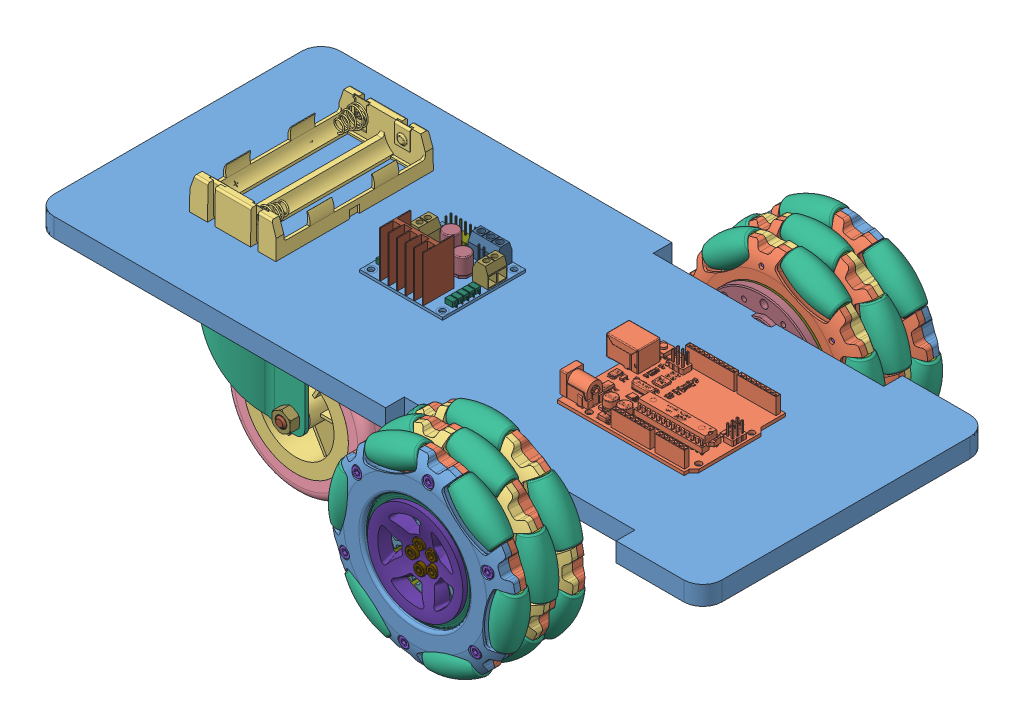
SolidWorks assembly Assem1, configuration Default. Lengths in mm.
Overall size (350 189.45 233.78).
324 component instances, 39 part files, 13 mates.
Components (placement in the parent):
- Base-1: Base [Default] at (-9.4539 132.6385 147.3537) size (350 10 150)
- Arduino Uno-1: Arduino Uno [Default] at (217.3211 144.2885 250.2775) x (0.005201 0 0.999986) z (-0.999986 0 0.005201) size (53.34 15.25 74.93)
- Assem2-1: Assem2 [Default] at (66.4468 55.8385 236.4759) x (1 0 0) z (0 1 0) size (101.4 70 114.3)
  - wheel-1: wheel [Default] at origin size (55 26.04 55)
  - tire-3: tire [Default] at (0 13 0) size (75 26 75)
  - Washer-4: Washer [Default] at (-0.0006 25.9444 0) x (0.999924 0.012354 0) z (0 0 1) size (15 1 15)
  - Washer-5: Washer [Default] at (-0.0006 0.0556 0) x (0.999924 -0.012354 0) z (0 0 -1) size (15 1 15)
  - wheel carrier-1: wheel carrier [Default] at (-28.9 13 57.6974) x (1 0 0) z (0 -1 0) size (61.1 84 49)
  - bearing -1: bearing  [Default] at (-28.9 13 57.6544) x (0 1 0) z (1 0 0) size (20 28 20)
  - Support plate -2: Support plate  [Default] at (-28.9 13 74.8) x (1 0 0) z (0 -1 0) size (70 28 70)
  - Ring-2: Ring [Default] at (-28.9 13.5 75.1) x (1 0 0) z (0 -1 0) size (12.09 1 12.84)
  - pipe-1: pipe [Default] at (0.3799 30.8549 0) x (0.999924 -0.012354 0) z (0 0 1) size (9 26 9)
  - screw M6-1: screw M6 [Default] at (0.2 -9 0.0106) size (9.53 41 11)
  - screw nut m6-1: screw nut m6 [Default] at (0.2 -8 0) size (9.53 5.33 11)
- Driect Drive Omni Wheel-1: Driect Drive Omni Wheel [Default] at (229.9584 120.1385 292.0369) x (0 0 1) z (-0.934942 -0.3548 0) size (54.71 135.89 136)
  - Direct Drive Motor-2: Direct Drive Motor [Default] at origin size (53.66 65 65)
    - DDM Bace-1: DDM Bace [Default] at origin size (45.5 65 65)
    - DDm Stator laminet-1: DDm Stator laminet [Default] at (32.5 0 0) x (0 1 0) z (0 0 1) size (53.5 22 53.5)
    - W 61809-2RS1-1: W 61809-2RS1 [Default] at (36 0 0) size (7 58 58)
    - DDM Rotor-1: DDM Rotor [Default] at (21.75 0 0) x (0 0 -1) z (0 1 0) size (65 42.5 65)
    - W 61809-2RS1-2: W 61809-2RS1 [Default] at origin size (7 58 58)
    - DDM Cap-1: DDM Cap [Default] at (30 0 0) size (16.16 50 50)
    - DDM M3-15mmscrew-1: DDM M3-15mmscrew [Valor predeterminado] at (39.1 -4.8541 3.5267) x (0 -1 0) z (0 0 1) size (5.5 13.1 5.5)
    - DDM M3-15mmscrew-2: DDM M3-15mmscrew [Valor predeterminado] at (39.1 1.8541 5.7063) x (0 -0.309017 0.951057) z (0 0.951057 0.309017) size (5.5 13.1 5.5)
    - DDM M3-15mmscrew-3: DDM M3-15mmscrew [Valor predeterminado] at (39.1 6 0) x (0 0.809017 0.587785) z (0 0.587785 -0.809017) size (5.5 13.1 5.5)
    - DDM M3-15mmscrew-4: DDM M3-15mmscrew [Valor predeterminado] at (39.1 1.8541 -5.7063) x (0 0.809017 -0.587785) z (0 -0.587785 -0.809017) size (5.5 13.1 5.5)
    - DDM M3-15mmscrew-5: DDM M3-15mmscrew [Valor predeterminado] at (39.1 -4.8541 -3.5267) x (0 -0.309017 -0.951057) z (0 -0.951057 0.309017) size (5.5 13.1 5.5)
  - DDOW Part 2-1: DDOW Part 2 [Default] at (38 0 0) x (0 0 1) z (0 1 0) size (97 9.21 95.55)
  - DDOW Part 5-1: DDOW Part 5 [Default] at (38 0 0) x (0 0 -1) z (0 1 0) size (97 9.21 95.55)
  - DDOW Part 3-1: DDOW Part 3 [Default] at (23 0 0) x (0 -0.37175 0.928333) z (0 0.928333 0.37175) size (97 9.21 95.55)
  - DDOW Part 5-2: DDOW Part 5 [Default] at (23 0 0) x (0 0.37175 -0.928333) z (0 0.928333 0.37175) size (97 9.21 95.55)
  - DDOW Part 3-2: DDOW Part 3 [Default] at (8 0 0) x (0 -0.666839 0.745202) z (0 0.745202 0.666839) size (97 9.21 95.55)
  - DDOW Part 5-3: DDOW Part 5 [Default] at (8 0 0) x (0 -0.311944 -0.9501) z (0 0.9501 -0.311944) size (97 9.21 95.55)
  - DDOW Roller Shaft-1: DDOW Roller Shaft [Default] at (38 -42.5 18) x (1 0 0) z (0 1 0) size (3 36 3)
  - DDOW Roller Shaft-2: DDOW Roller Shaft [Default] at (23 -46.1456 0.9106) x (1 0 0) z (0 0.928333 0.37175) size (3 36 3)
  - DDOW Roller Shaft-3: DDOW Roller Shaft [Default] at (8 -43.6742 -14.927) x (1 0 0) z (0 0.745202 0.666839) size (3 36 3)
  - DDOW Roller Shaft-4: DDOW Roller Shaft [Default] at (38 -5.6615 45.8061) x (1 0 0) z (0 0.5 -0.866025) size (3 36 3)
  - DDOW Roller Shaft-5: DDOW Roller Shaft [Default] at (38 36.8385 27.8061) x (1 0 0) z (0 -0.5 -0.866025) size (3 36 3)
  - DDOW Roller Shaft-6: DDOW Roller Shaft [Default] at (38 42.5 -18) x (1 0 0) z (0 -1 0) size (3 36 3)
  - DDOW Roller Shaft-7: DDOW Roller Shaft [Default] at (38 5.6615 -45.8061) x (1 0 0) z (0 -0.5 0.866025) size (3 36 3)
  - DDOW Roller Shaft-8: DDOW Roller Shaft [Default] at (38 -36.8385 -27.8061) x (1 0 0) z (0 0.5 0.866025) size (3 36 3)
  - DDOW Roller Shaft-9: DDOW Roller Shaft [Default] at (23 -22.2842 40.4186) x (1 0 0) z (0 0.786111 -0.618085) size (3 36 3)
  - DDOW Roller Shaft-10: DDOW Roller Shaft [Default] at (23 23.8614 39.508) x (1 0 0) z (0 -0.142222 -0.989835) size (3 36 3)
  - DDOW Roller Shaft-11: DDOW Roller Shaft [Default] at (23 46.1456 -0.9106) x (1 0 0) z (0 -0.928333 -0.37175) size (3 36 3)
  - DDOW Roller Shaft-12: DDOW Roller Shaft [Default] at (23 22.2842 -40.4186) x (1 0 0) z (0 -0.786111 0.618085) size (3 36 3)
  - DDOW Roller Shaft-13: DDOW Roller Shaft [Default] at (23 -23.8614 -39.508) x (1 0 0) z (0 0.142222 0.989835) size (3 36 3)
  - DDOW Roller Shaft-14: DDOW Roller Shaft [Default] at (8 -34.7643 30.3594) x (1 0 0) z (0 0.9501 -0.311944) size (3 36 3)
  - DDOW Roller Shaft-15: DDOW Roller Shaft [Default] at (8 8.9099 45.2865) x (1 0 0) z (0 0.204899 -0.978783) size (3 36 3)
  - DDOW Roller Shaft-16: DDOW Roller Shaft [Default] at (8 43.6742 14.927) x (1 0 0) z (0 -0.745202 -0.666839) size (3 36 3)
  - DDOW Roller Shaft-17: DDOW Roller Shaft [Default] at (8 34.7643 -30.3594) x (1 0 0) z (0 -0.9501 0.311944) size (3 36 3)
  - DDOW Roller Shaft-18: DDOW Roller Shaft [Default] at (8 -8.9099 -45.2865) x (1 0 0) z (0 -0.204899 0.978783) size (3 36 3)
  - DDOW Suport Shaft-1: DDOW Suport Shaft [Default] at (38 -42.5 0) x (0 0 -1) z (1 0 0) size (27.4 9 9)
  - DDOW Roller-1: DDOW Roller [Default] at (38 -42.5 0) x (0 0 -1) z (1 0 0) size (29 15 15)
  - DDOW Suport Shaft-2: DDOW Suport Shaft [Default] at (23 -39.4542 -15.7994) x (0 0.37175 -0.928333) z (1 0 0) size (27.4 9 9)
  - DDOW Suport Shaft-3: DDOW Suport Shaft [Default] at (8 -31.6711 -28.3407) x (0 0.666839 -0.745202) z (1 0 0) size (27.4 9 9)
  - DDOW Roller-2: DDOW Roller [Default] at (23 -39.4542 -15.7994) x (0 0.37175 -0.928333) z (0.999544 0.028039 0.011228) size (29 15 15)
  - DDOW Roller-3: DDOW Roller [Default] at (8 -31.6711 -28.3407) x (0 -0.666839 0.745202) z (0.923728 0.285449 0.255432) size (29 15 15)
  - W 638_3 R-2RS1-1: W 638_3 R-2RS1 [Default] at (8 -22.0019 -39.1461) x (0 -0.666839 0.745202) z (-1 0 0) size (3 8.1 8.1)
  - W 638_3 R-2RS1-2: W 638_3 R-2RS1 [Default] at (8 -41.3402 -17.5352) x (0 0.666839 -0.745202) z (-0.937928 -0.258458 -0.23128) size (3 8.1 8.1)
  - W 638_3 R-2RS1-3: W 638_3 R-2RS1 [Default] at (23 -34.0638 -29.2602) x (0 -0.37175 0.928333) z (-1 0 0) size (3 8.1 8.1)
  - W 638_3 R-2RS1-4: W 638_3 R-2RS1 [Default] at (23 -44.8445 -2.3385) x (0 0.37175 -0.928333) z (-0.923728 -0.355597 -0.142398) size (3 8.1 8.1)
  - W 638_3 R-2RS1-5: W 638_3 R-2RS1 [Default] at (38 -42.5 14.5) x (0 0 -1) z (-0.923728 -0.383049 0) size (3 8.1 8.1)
  - W 638_3 R-2RS1-6: W 638_3 R-2RS1 [Default] at (38 -42.5 -14.5) x (0 0 1) z (-1 0 0) size (3 8.1 8.1)
  - W 638_3 R-2RS1-7: W 638_3 R-2RS1 [Default] at (38 -33.8074 29.5561) x (0 0.866025 0.5) z (-1 0 0) size (3 8.1 8.1)
  - W 638_3 R-2RS1-8: W 638_3 R-2RS1 [Default] at (38 8.6926 44.0561) x (0 0.866025 -0.5) z (-1 0 0) size (3 8.1 8.1)
  - W 638_3 R-2RS1-9: W 638_3 R-2RS1 [Default] at (38 42.5 14.5) x (0 0 -1) z (-1 0 0) size (3 8.1 8.1)
  - W 638_3 R-2RS1-10: W 638_3 R-2RS1 [Default] at (38 33.8074 -29.5561) x (0 -0.866025 -0.5) z (-1 0 0) size (3 8.1 8.1)
  - W 638_3 R-2RS1-11: W 638_3 R-2RS1 [Default] at (38 -8.6926 -44.0561) x (0 -0.866025 0.5) z (-1 0 0) size (3 8.1 8.1)
  - W 638_3 R-2RS1-12: W 638_3 R-2RS1 [Default] at (38 -8.6926 44.0561) x (0 -0.866025 -0.5) z (-0.923728 -0.191525 0.33173) size (3 8.1 8.1)
  - W 638_3 R-2RS1-13: W 638_3 R-2RS1 [Default] at (38 33.8074 29.5561) x (0 -0.866025 0.5) z (-0.923728 0.191525 0.33173) size (3 8.1 8.1)
  - W 638_3 R-2RS1-14: W 638_3 R-2RS1 [Default] at (38 42.5 -14.5) x (0 0 1) z (-0.923728 0.383049 0) size (3 8.1 8.1)
  - W 638_3 R-2RS1-15: W 638_3 R-2RS1 [Default] at (38 8.6926 -44.0561) x (0 0.866025 0.5) z (-0.923728 0.191525 -0.33173) size (3 8.1 8.1)
  - W 638_3 R-2RS1-16: W 638_3 R-2RS1 [Default] at (38 -33.8074 -29.5561) x (0 0.866025 -0.5) z (-0.923728 -0.191525 -0.33173) size (3 8.1 8.1)
  - W 638_3 R-2RS1-17: W 638_3 R-2RS1 [Default] at (23 -24.4475 37.6672) x (0 -0.618085 -0.786111) z (-0.923728 -0.301119 0.236757) size (3 8.1 8.1)
  - W 638_3 R-2RS1-18: W 638_3 R-2RS1 [Default] at (23 20.397 40.0058) x (0 -0.989835 0.142222) z (-0.923728 0.054478 0.379155) size (3 8.1 8.1)
  - W 638_3 R-2RS1-19: W 638_3 R-2RS1 [Default] at (23 44.8445 2.3385) x (0 -0.37175 0.928333) z (-0.923728 0.355597 0.142398) size (3 8.1 8.1)
  - W 638_3 R-2RS1-20: W 638_3 R-2RS1 [Default] at (23 24.4475 -37.6672) x (0 0.618085 0.786111) z (-0.923728 0.301119 -0.236757) size (3 8.1 8.1)
  - W 638_3 R-2RS1-21: W 638_3 R-2RS1 [Default] at (23 -20.397 -40.0058) x (0 0.989835 -0.142222) z (-0.923728 -0.054478 -0.379155) size (3 8.1 8.1)
  - W 638_3 R-2RS1-22: W 638_3 R-2RS1 [Default] at (23 -42.372 14.87) x (0 0.618085 0.786111) z (-1 0 0) size (3 8.1 8.1)
  - W 638_3 R-2RS1-23: W 638_3 R-2RS1 [Default] at (23 -8.3082 44.1302) x (0 0.989835 -0.142222) z (-1 0 0) size (3 8.1 8.1)
  - W 638_3 R-2RS1-24: W 638_3 R-2RS1 [Default] at (23 34.0638 29.2602) x (0 0.37175 -0.928333) z (-1 0 0) size (3 8.1 8.1)
  - W 638_3 R-2RS1-25: W 638_3 R-2RS1 [Default] at (23 42.372 -14.87) x (0 -0.618085 -0.786111) z (-1 0 0) size (3 8.1 8.1)
  - W 638_3 R-2RS1-26: W 638_3 R-2RS1 [Default] at (23 8.3082 -44.1302) x (0 -0.989835 0.142222) z (-1 0 0) size (3 8.1 8.1)
  - W 638_3 R-2RS1-27: W 638_3 R-2RS1 [Default] at (8 -35.8561 27.0341) x (0 -0.311944 -0.9501) z (-0.937928 -0.329523 0.108192) size (3 8.1 8.1)
  - W 638_3 R-2RS1-28: W 638_3 R-2RS1 [Default] at (8 5.4842 44.5693) x (0 -0.978783 -0.204899) z (-0.937928 -0.071065 0.339471) size (3 8.1 8.1)
  - W 638_3 R-2RS1-29: W 638_3 R-2RS1 [Default] at (8 41.3402 17.5352) x (0 -0.666839 0.745202) z (-0.937928 0.258458 0.23128) size (3 8.1 8.1)
  - W 638_3 R-2RS1-30: W 638_3 R-2RS1 [Default] at (8 35.8561 -27.0341) x (0 0.311944 0.9501) z (-0.937928 0.329523 -0.108192) size (3 8.1 8.1)
  - W 638_3 R-2RS1-31: W 638_3 R-2RS1 [Default] at (8 -5.4842 -44.5693) x (0 0.978783 0.204899) z (-0.937928 0.071065 -0.339471) size (3 8.1 8.1)
  - W 638_3 R-2RS1-32: W 638_3 R-2RS1 [Default] at (8 -44.9025 -0.5188) x (0 0.311944 0.9501) z (-1 0 0) size (3 8.1 8.1)
  - W 638_3 R-2RS1-33: W 638_3 R-2RS1 [Default] at (8 -22.9006 38.6273) x (0 0.978783 0.204899) z (-1 0 0) size (3 8.1 8.1)
  - W 638_3 R-2RS1-34: W 638_3 R-2RS1 [Default] at (8 22.0019 39.1461) x (0 0.666839 -0.745202) z (-1 0 0) size (3 8.1 8.1)
  - W 638_3 R-2RS1-35: W 638_3 R-2RS1 [Default] at (8 44.9025 0.5188) x (0 -0.311944 -0.9501) z (-1 0 0) size (3 8.1 8.1)
  - W 638_3 R-2RS1-36: W 638_3 R-2RS1 [Default] at (8 22.9006 -38.6273) x (0 -0.978783 -0.204899) z (-1 0 0) size (3 8.1 8.1)
  - DDOW Roller-4: DDOW Roller [Default] at (8 -40.3793 13.2576) x (0 0.311944 0.9501) z (0.923728 0.363935 -0.11949) size (29 15 15)
  - DDOW Roller-5: DDOW Roller [Default] at (8 -8.7082 41.5983) x (0 0.978783 0.204899) z (0.923728 0.078486 -0.374922) size (29 15 15)
  - DDOW Roller-6: DDOW Roller [Default] at (8 31.6711 28.3407) x (0 0.666839 -0.745202) z (0.923728 -0.285449 -0.255432) size (29 15 15)
  - DDOW Roller-7: DDOW Roller [Default] at (8 40.3793 -13.2576) x (0 -0.311944 -0.9501) z (0.923728 -0.363935 0.11949) size (29 15 15)
  - DDOW Roller-8: DDOW Roller [Default] at (8 8.7082 -41.5983) x (0 -0.978783 -0.204899) z (0.923728 -0.078486 0.374922) size (29 15 15)
  - DDOW Roller-9: DDOW Roller [Default] at (23 -33.4097 26.2686) x (0 -0.618085 -0.786111) z (0.999544 0.023743 -0.018668) size (29 15 15)
  - DDOW Roller-10: DDOW Roller [Default] at (23 6.0444 42.068) x (0 -0.989835 0.142222) z (0.999544 -0.004296 -0.029896) size (29 15 15)
  - DDOW Roller-11: DDOW Roller [Default] at (23 39.4542 15.7994) x (0 -0.37175 0.928333) z (0.999544 -0.028039 -0.011228) size (29 15 15)
  - DDOW Roller-12: DDOW Roller [Default] at (23 33.4097 -26.2686) x (0 0.618085 0.786111) z (0.999544 -0.023743 0.018668) size (29 15 15)
  - DDOW Roller-13: DDOW Roller [Default] at (23 -6.0444 -42.068) x (0 0.989835 -0.142222) z (0.999544 0.004296 0.029896) size (29 15 15)
  - DDOW Suport Shaft-4: DDOW Suport Shaft [Default] at (8 -40.3793 13.2576) x (0 -0.311944 -0.9501) z (1 0 0) size (27.4 9 9)
  - DDOW Suport Shaft-5: DDOW Suport Shaft [Default] at (8 -8.7082 41.5983) x (0 -0.978783 -0.204899) z (1 0 0) size (27.4 9 9)
  - DDOW Suport Shaft-6: DDOW Suport Shaft [Default] at (8 31.6711 28.3407) x (0 -0.666839 0.745202) z (1 0 0) size (27.4 9 9)
  - DDOW Suport Shaft-7: DDOW Suport Shaft [Default] at (8 40.3793 -13.2576) x (0 0.311944 0.9501) z (1 0 0) size (27.4 9 9)
  - DDOW Suport Shaft-8: DDOW Suport Shaft [Default] at (8 8.7082 -41.5983) x (0 0.978783 0.204899) z (1 0 0) size (27.4 9 9)
  - DDOW Suport Shaft-9: DDOW Suport Shaft [Default] at (23 -33.4097 26.2686) x (0 -0.618085 -0.786111) z (1 0 0) size (27.4 9 9)
  - DDOW Suport Shaft-10: DDOW Suport Shaft [Default] at (23 6.0444 42.068) x (0 -0.989835 0.142222) z (1 0 0) size (27.4 9 9)
  - DDOW Suport Shaft-11: DDOW Suport Shaft [Default] at (23 39.4542 15.7994) x (0 -0.37175 0.928333) z (1 0 0) size (27.4 9 9)
  - DDOW Suport Shaft-12: DDOW Suport Shaft [Default] at (23 33.4097 -26.2686) x (0 0.618085 0.786111) z (1 0 0) size (27.4 9 9)
  - DDOW Suport Shaft-13: DDOW Suport Shaft [Default] at (23 -6.0444 -42.068) x (0 0.989835 -0.142222) z (1 0 0) size (27.4 9 9)
  - DDOW Roller-14: DDOW Roller [Default] at (38 -21.25 36.8061) x (0 -0.866025 -0.5) z (1 0 0) size (29 15 15)
  - DDOW Roller-15: DDOW Roller [Default] at (38 21.25 36.8061) x (0 -0.866025 0.5) z (1 0 0) size (29 15 15)
  - DDOW Roller-16: DDOW Roller [Default] at (38 42.5 0) x (0 0 1) z (1 0 0) size (29 15 15)
  - DDOW Roller-17: DDOW Roller [Default] at (38 21.25 -36.8061) x (0 0.866025 0.5) z (1 0 0) size (29 15 15)
  - DDOW Roller-18: DDOW Roller [Default] at (38 -21.25 -36.8061) x (0 0.866025 -0.5) z (1 0 0) size (29 15 15)
  - DDOW Suport Shaft-14: DDOW Suport Shaft [Default] at (38 -21.25 36.8061) x (0 -0.866025 -0.5) z (1 0 0) size (27.4 9 9)
  - DDOW Suport Shaft-15: DDOW Suport Shaft [Default] at (38 21.25 36.8061) x (0 -0.866025 0.5) z (1 0 0) size (27.4 9 9)
  - DDOW Suport Shaft-16: DDOW Suport Shaft [Default] at (38 42.5 0) x (0 0 1) z (1 0 0) size (27.4 9 9)
  - DDOW Suport Shaft-17: DDOW Suport Shaft [Default] at (38 21.25 -36.8061) x (0 0.866025 0.5) z (1 0 0) size (27.4 9 9)
  - DDOW Suport Shaft-18: DDOW Suport Shaft [Default] at (38 -21.25 -36.8061) x (0 0.866025 -0.5) z (1 0 0) size (27.4 9 9)
  - DDOW Roller Shaft-19: DDOW Roller Shaft [Default] at (8 -34.7643 30.3594) x (1 0 0) z (0 0.9501 -0.311944) size (3 36 3)
  - DDOW Roller Shaft-20: DDOW Roller Shaft [Default] at (8 8.9099 45.2865) x (1 0 0) z (0 0.204899 -0.978783) size (3 36 3)
  - DDOW Roller Shaft-21: DDOW Roller Shaft [Default] at (8 43.6742 14.927) x (1 0 0) z (0 -0.745202 -0.666839) size (3 36 3)
  - DDOW Roller Shaft-22: DDOW Roller Shaft [Default] at (8 34.7643 -30.3594) x (1 0 0) z (0 -0.9501 0.311944) size (3 36 3)
  - DDOW Roller Shaft-23: DDOW Roller Shaft [Default] at (8 -8.9099 -45.2865) x (1 0 0) z (0 -0.204899 0.978783) size (3 36 3)
  - DDOW Roller Shaft-24: DDOW Roller Shaft [Default] at (23 -22.2842 40.4186) x (1 0 0) z (0 0.786111 -0.618085) size (3 36 3)
  - DDOW Roller Shaft-25: DDOW Roller Shaft [Default] at (23 23.8614 39.508) x (1 0 0) z (0 -0.142222 -0.989835) size (3 36 3)
  - DDOW Roller Shaft-26: DDOW Roller Shaft [Default] at (23 46.1456 -0.9106) x (1 0 0) z (0 -0.928333 -0.37175) size (3 36 3)
  - DDOW Roller Shaft-27: DDOW Roller Shaft [Default] at (23 22.2842 -40.4186) x (1 0 0) z (0 -0.786111 0.618085) size (3 36 3)
  - DDOW Roller Shaft-28: DDOW Roller Shaft [Default] at (23 -23.8614 -39.508) x (1 0 0) z (0 0.142222 0.989835) size (3 36 3)
  - DDOW Roller Shaft-29: DDOW Roller Shaft [Default] at (38 -5.6615 45.8061) x (1 0 0) z (0 0.5 -0.866025) size (3 36 3)
  - DDOW Roller Shaft-30: DDOW Roller Shaft [Default] at (38 36.8385 27.8061) x (1 0 0) z (0 -0.5 -0.866025) size (3 36 3)
  - DDOW Roller Shaft-31: DDOW Roller Shaft [Default] at (38 42.5 -18) x (1 0 0) z (0 -1 0) size (3 36 3)
  - DDOW Roller Shaft-32: DDOW Roller Shaft [Default] at (38 5.6615 -45.8061) x (1 0 0) z (0 -0.5 0.866025) size (3 36 3)
  - DDOW Roller Shaft-33: DDOW Roller Shaft [Default] at (38 -36.8385 -27.8061) x (1 0 0) z (0 0.5 0.866025) size (3 36 3)
  - DDOW M3-15mmscrew-1: DDOW M3-15mmscrew [Valor predeterminado] at (42 -34.641 20) x (0 -1 0) z (0 0 1) size (5.5 13.1 5.5)
  - DDOW M3-15mmscrew-2: DDOW M3-15mmscrew [Valor predeterminado] at (27 -14.87 37.1333) x (0 -1 0) z (0 0 1) size (5.5 13.1 5.5)
  - DDOW M3-15mmscrew-3: DDOW M3-15mmscrew [Valor predeterminado] at (12 12.4778 38.004) x (0 -1 0) z (0 0 1) size (5.5 13.1 5.5)
  - DDOW M3-15mmscrew-5: DDOW M3-15mmscrew [Valor predeterminado] at (12 39.1513 8.196) x (0 -0.5 0.866025) z (0 0.866025 0.5) size (5.5 13.1 5.5)
  - DDOW M3-15mmscrew-6: DDOW M3-15mmscrew [Valor predeterminado] at (12 26.6736 -29.8081) x (0 0.5 0.866025) z (0 0.866025 -0.5) size (5.5 13.1 5.5)
  - DDOW M3-15mmscrew-7: DDOW M3-15mmscrew [Valor predeterminado] at (12 -12.4778 -38.004) x (0 1 0) z (0 0 -1) size (5.5 13.1 5.5)
  - DDOW M3-15mmscrew-8: DDOW M3-15mmscrew [Valor predeterminado] at (12 -39.1513 -8.196) x (0 0.5 -0.866025) z (0 -0.866025 -0.5) size (5.5 13.1 5.5)
  - DDOW M3-15mmscrew-9: DDOW M3-15mmscrew [Valor predeterminado] at (12 -26.6736 29.8081) x (0 -0.5 -0.866025) z (0 -0.866025 0.5) size (5.5 13.1 5.5)
  - DDOW M3-15mmscrew-10: DDOW M3-15mmscrew [Valor predeterminado] at (27 24.7234 31.4445) x (0 -0.5 0.866025) z (0 0.866025 0.5) size (5.5 13.1 5.5)
  - DDOW M3-15mmscrew-11: DDOW M3-15mmscrew [Valor predeterminado] at (27 39.5934 -5.6889) x (0 0.5 0.866025) z (0 0.866025 -0.5) size (5.5 13.1 5.5)
  - DDOW M3-15mmscrew-12: DDOW M3-15mmscrew [Valor predeterminado] at (27 14.87 -37.1333) x (0 1 0) z (0 0 -1) size (5.5 13.1 5.5)
  - DDOW M3-15mmscrew-13: DDOW M3-15mmscrew [Valor predeterminado] at (27 -24.7234 -31.4445) x (0 0.5 -0.866025) z (0 -0.866025 -0.5) size (5.5 13.1 5.5)
  - DDOW M3-15mmscrew-14: DDOW M3-15mmscrew [Valor predeterminado] at (27 -39.5934 5.6889) x (0 -0.5 -0.866025) z (0 -0.866025 0.5) size (5.5 13.1 5.5)
  - DDOW M3-15mmscrew-15: DDOW M3-15mmscrew [Valor predeterminado] at (42 0 40) x (0 -0.5 0.866025) z (0 0.866025 0.5) size (5.5 13.1 5.5)
  - DDOW M3-15mmscrew-16: DDOW M3-15mmscrew [Valor predeterminado] at (42 34.641 20) x (0 0.5 0.866025) z (0 0.866025 -0.5) size (5.5 13.1 5.5)
  - DDOW M3-15mmscrew-17: DDOW M3-15mmscrew [Valor predeterminado] at (42 34.641 -20) x (0 1 0) z (0 0 -1) size (5.5 13.1 5.5)
  - DDOW M3-15mmscrew-18: DDOW M3-15mmscrew [Valor predeterminado] at (42 0 -40) x (0 0.5 -0.866025) z (0 -0.866025 -0.5) size (5.5 13.1 5.5)
  - DDOW M3-15mmscrew-19: DDOW M3-15mmscrew [Valor predeterminado] at (42 -34.641 -20) x (0 -0.5 -0.866025) z (0 -0.866025 0.5) size (5.5 13.1 5.5)
- Pololu-25D-12V-21kgcm-DCmotor-2: Pololu-25D-12V-21kgcm-DCmotor [Varsayılan] at (229.9584 120.1385 242.6369) x (-0.746606 -0.665266 0) z (0 0 1) size (26 29.5 78.1)
- Driect Drive Omni Wheel-2: Driect Drive Omni Wheel [Default] at (230.5822 120.1385 152.6705) x (0 0 -1) z (0.946615 0.322367 0) size (54.71 135.89 136)
  - Direct Drive Motor-2: Direct Drive Motor [Default] at origin size (53.66 65 65)
    - DDM Bace-1: DDM Bace [Default] at origin size (45.5 65 65)
    - DDm Stator laminet-1: DDm Stator laminet [Default] at (32.5 0 0) x (0 1 0) z (0 0 1) size (53.5 22 53.5)
    - W 61809-2RS1-1: W 61809-2RS1 [Default] at (36 0 0) size (7 58 58)
    - DDM Rotor-1: DDM Rotor [Default] at (21.75 0 0) x (0 0 -1) z (0 1 0) size (65 42.5 65)
    - W 61809-2RS1-2: W 61809-2RS1 [Default] at origin size (7 58 58)
    - DDM Cap-1: DDM Cap [Default] at (30 0 0) size (16.16 50 50)
    - DDM M3-15mmscrew-1: DDM M3-15mmscrew [Valor predeterminado] at (39.1 -4.8541 3.5267) x (0 -1 0) z (0 0 1) size (5.5 13.1 5.5)
    - DDM M3-15mmscrew-2: DDM M3-15mmscrew [Valor predeterminado] at (39.1 1.8541 5.7063) x (0 -0.309017 0.951057) z (0 0.951057 0.309017) size (5.5 13.1 5.5)
    - DDM M3-15mmscrew-3: DDM M3-15mmscrew [Valor predeterminado] at (39.1 6 0) x (0 0.809017 0.587785) z (0 0.587785 -0.809017) size (5.5 13.1 5.5)
    - DDM M3-15mmscrew-4: DDM M3-15mmscrew [Valor predeterminado] at (39.1 1.8541 -5.7063) x (0 0.809017 -0.587785) z (0 -0.587785 -0.809017) size (5.5 13.1 5.5)
    - DDM M3-15mmscrew-5: DDM M3-15mmscrew [Valor predeterminado] at (39.1 -4.8541 -3.5267) x (0 -0.309017 -0.951057) z (0 -0.951057 0.309017) size (5.5 13.1 5.5)
  - DDOW Part 2-1: DDOW Part 2 [Default] at (38 0 0) x (0 0 1) z (0 1 0) size (97 9.21 95.55)
  - DDOW Part 5-1: DDOW Part 5 [Default] at (38 0 0) x (0 0 -1) z (0 1 0) size (97 9.21 95.55)
  - DDOW Part 3-1: DDOW Part 3 [Default] at (23 0 0) x (0 -0.37175 0.928333) z (0 0.928333 0.37175) size (97 9.21 95.55)
  - DDOW Part 5-2: DDOW Part 5 [Default] at (23 0 0) x (0 0.37175 -0.928333) z (0 0.928333 0.37175) size (97 9.21 95.55)
  - DDOW Part 3-2: DDOW Part 3 [Default] at (8 0 0) x (0 -0.666839 0.745202) z (0 0.745202 0.666839) size (97 9.21 95.55)
  - DDOW Part 5-3: DDOW Part 5 [Default] at (8 0 0) x (0 -0.311944 -0.9501) z (0 0.9501 -0.311944) size (97 9.21 95.55)
  - DDOW Roller Shaft-1: DDOW Roller Shaft [Default] at (38 -42.5 18) x (1 0 0) z (0 1 0) size (3 36 3)
  - DDOW Roller Shaft-2: DDOW Roller Shaft [Default] at (23 -46.1456 0.9106) x (1 0 0) z (0 0.928333 0.37175) size (3 36 3)
  - DDOW Roller Shaft-3: DDOW Roller Shaft [Default] at (8 -43.6742 -14.927) x (1 0 0) z (0 0.745202 0.666839) size (3 36 3)
  - DDOW Roller Shaft-4: DDOW Roller Shaft [Default] at (38 -5.6615 45.8061) x (1 0 0) z (0 0.5 -0.866025) size (3 36 3)
  - DDOW Roller Shaft-5: DDOW Roller Shaft [Default] at (38 36.8385 27.8061) x (1 0 0) z (0 -0.5 -0.866025) size (3 36 3)
  - DDOW Roller Shaft-6: DDOW Roller Shaft [Default] at (38 42.5 -18) x (1 0 0) z (0 -1 0) size (3 36 3)
  - DDOW Roller Shaft-7: DDOW Roller Shaft [Default] at (38 5.6615 -45.8061) x (1 0 0) z (0 -0.5 0.866025) size (3 36 3)
  - DDOW Roller Shaft-8: DDOW Roller Shaft [Default] at (38 -36.8385 -27.8061) x (1 0 0) z (0 0.5 0.866025) size (3 36 3)
  - DDOW Roller Shaft-9: DDOW Roller Shaft [Default] at (23 -22.2842 40.4186) x (1 0 0) z (0 0.786111 -0.618085) size (3 36 3)
  - DDOW Roller Shaft-10: DDOW Roller Shaft [Default] at (23 23.8614 39.508) x (1 0 0) z (0 -0.142222 -0.989835) size (3 36 3)
  - DDOW Roller Shaft-11: DDOW Roller Shaft [Default] at (23 46.1456 -0.9106) x (1 0 0) z (0 -0.928333 -0.37175) size (3 36 3)
  - DDOW Roller Shaft-12: DDOW Roller Shaft [Default] at (23 22.2842 -40.4186) x (1 0 0) z (0 -0.786111 0.618085) size (3 36 3)
  - DDOW Roller Shaft-13: DDOW Roller Shaft [Default] at (23 -23.8614 -39.508) x (1 0 0) z (0 0.142222 0.989835) size (3 36 3)
  - DDOW Roller Shaft-14: DDOW Roller Shaft [Default] at (8 -34.7643 30.3594) x (1 0 0) z (0 0.9501 -0.311944) size (3 36 3)
  - DDOW Roller Shaft-15: DDOW Roller Shaft [Default] at (8 8.9099 45.2865) x (1 0 0) z (0 0.204899 -0.978783) size (3 36 3)
  - DDOW Roller Shaft-16: DDOW Roller Shaft [Default] at (8 43.6742 14.927) x (1 0 0) z (0 -0.745202 -0.666839) size (3 36 3)
  - DDOW Roller Shaft-17: DDOW Roller Shaft [Default] at (8 34.7643 -30.3594) x (1 0 0) z (0 -0.9501 0.311944) size (3 36 3)
  - DDOW Roller Shaft-18: DDOW Roller Shaft [Default] at (8 -8.9099 -45.2865) x (1 0 0) z (0 -0.204899 0.978783) size (3 36 3)
  - DDOW Suport Shaft-1: DDOW Suport Shaft [Default] at (38 -42.5 0) x (0 0 -1) z (1 0 0) size (27.4 9 9)
  - DDOW Roller-1: DDOW Roller [Default] at (38 -42.5 0) x (0 0 -1) z (1 0 0) size (29 15 15)
  - DDOW Suport Shaft-2: DDOW Suport Shaft [Default] at (23 -39.4542 -15.7994) x (0 0.37175 -0.928333) z (1 0 0) size (27.4 9 9)
  - DDOW Suport Shaft-3: DDOW Suport Shaft [Default] at (8 -31.6711 -28.3407) x (0 0.666839 -0.745202) z (1 0 0) size (27.4 9 9)
  - DDOW Roller-2: DDOW Roller [Default] at (23 -39.4542 -15.7994) x (0 0.37175 -0.928333) z (0.999544 0.028039 0.011228) size (29 15 15)
  - DDOW Roller-3: DDOW Roller [Default] at (8 -31.6711 -28.3407) x (0 -0.666839 0.745202) z (0.923728 0.285449 0.255432) size (29 15 15)
  - W 638_3 R-2RS1-1: W 638_3 R-2RS1 [Default] at (8 -22.0019 -39.1461) x (0 -0.666839 0.745202) z (-1 0 0) size (3 8.1 8.1)
  - W 638_3 R-2RS1-2: W 638_3 R-2RS1 [Default] at (8 -41.3402 -17.5352) x (0 0.666839 -0.745202) z (-0.937928 -0.258458 -0.23128) size (3 8.1 8.1)
  - W 638_3 R-2RS1-3: W 638_3 R-2RS1 [Default] at (23 -34.0638 -29.2602) x (0 -0.37175 0.928333) z (-1 0 0) size (3 8.1 8.1)
  - W 638_3 R-2RS1-4: W 638_3 R-2RS1 [Default] at (23 -44.8445 -2.3385) x (0 0.37175 -0.928333) z (-0.923728 -0.355597 -0.142398) size (3 8.1 8.1)
  - W 638_3 R-2RS1-5: W 638_3 R-2RS1 [Default] at (38 -42.5 14.5) x (0 0 -1) z (-0.923728 -0.383049 0) size (3 8.1 8.1)
  - W 638_3 R-2RS1-6: W 638_3 R-2RS1 [Default] at (38 -42.5 -14.5) x (0 0 1) z (-1 0 0) size (3 8.1 8.1)
  - W 638_3 R-2RS1-7: W 638_3 R-2RS1 [Default] at (38 -33.8074 29.5561) x (0 0.866025 0.5) z (-1 0 0) size (3 8.1 8.1)
  - W 638_3 R-2RS1-8: W 638_3 R-2RS1 [Default] at (38 8.6926 44.0561) x (0 0.866025 -0.5) z (-1 0 0) size (3 8.1 8.1)
  - W 638_3 R-2RS1-9: W 638_3 R-2RS1 [Default] at (38 42.5 14.5) x (0 0 -1) z (-1 0 0) size (3 8.1 8.1)
  - W 638_3 R-2RS1-10: W 638_3 R-2RS1 [Default] at (38 33.8074 -29.5561) x (0 -0.866025 -0.5) z (-1 0 0) size (3 8.1 8.1)
  - W 638_3 R-2RS1-11: W 638_3 R-2RS1 [Default] at (38 -8.6926 -44.0561) x (0 -0.866025 0.5) z (-1 0 0) size (3 8.1 8.1)
  - W 638_3 R-2RS1-12: W 638_3 R-2RS1 [Default] at (38 -8.6926 44.0561) x (0 -0.866025 -0.5) z (-0.923728 -0.191525 0.33173) size (3 8.1 8.1)
  - W 638_3 R-2RS1-13: W 638_3 R-2RS1 [Default] at (38 33.8074 29.5561) x (0 -0.866025 0.5) z (-0.923728 0.191525 0.33173) size (3 8.1 8.1)
  - W 638_3 R-2RS1-14: W 638_3 R-2RS1 [Default] at (38 42.5 -14.5) x (0 0 1) z (-0.923728 0.383049 0) size (3 8.1 8.1)
  - W 638_3 R-2RS1-15: W 638_3 R-2RS1 [Default] at (38 8.6926 -44.0561) x (0 0.866025 0.5) z (-0.923728 0.191525 -0.33173) size (3 8.1 8.1)
  - W 638_3 R-2RS1-16: W 638_3 R-2RS1 [Default] at (38 -33.8074 -29.5561) x (0 0.866025 -0.5) z (-0.923728 -0.191525 -0.33173) size (3 8.1 8.1)
  - W 638_3 R-2RS1-17: W 638_3 R-2RS1 [Default] at (23 -24.4475 37.6672) x (0 -0.618085 -0.786111) z (-0.923728 -0.301119 0.236757) size (3 8.1 8.1)
  - W 638_3 R-2RS1-18: W 638_3 R-2RS1 [Default] at (23 20.397 40.0058) x (0 -0.989835 0.142222) z (-0.923728 0.054478 0.379155) size (3 8.1 8.1)
  - W 638_3 R-2RS1-19: W 638_3 R-2RS1 [Default] at (23 44.8445 2.3385) x (0 -0.37175 0.928333) z (-0.923728 0.355597 0.142398) size (3 8.1 8.1)
  - W 638_3 R-2RS1-20: W 638_3 R-2RS1 [Default] at (23 24.4475 -37.6672) x (0 0.618085 0.786111) z (-0.923728 0.301119 -0.236757) size (3 8.1 8.1)
  - W 638_3 R-2RS1-21: W 638_3 R-2RS1 [Default] at (23 -20.397 -40.0058) x (0 0.989835 -0.142222) z (-0.923728 -0.054478 -0.379155) size (3 8.1 8.1)
  - W 638_3 R-2RS1-22: W 638_3 R-2RS1 [Default] at (23 -42.372 14.87) x (0 0.618085 0.786111) z (-1 0 0) size (3 8.1 8.1)
  - W 638_3 R-2RS1-23: W 638_3 R-2RS1 [Default] at (23 -8.3082 44.1302) x (0 0.989835 -0.142222) z (-1 0 0) size (3 8.1 8.1)
  - W 638_3 R-2RS1-24: W 638_3 R-2RS1 [Default] at (23 34.0638 29.2602) x (0 0.37175 -0.928333) z (-1 0 0) size (3 8.1 8.1)
  - W 638_3 R-2RS1-25: W 638_3 R-2RS1 [Default] at (23 42.372 -14.87) x (0 -0.618085 -0.786111) z (-1 0 0) size (3 8.1 8.1)
  - W 638_3 R-2RS1-26: W 638_3 R-2RS1 [Default] at (23 8.3082 -44.1302) x (0 -0.989835 0.142222) z (-1 0 0) size (3 8.1 8.1)
  - W 638_3 R-2RS1-27: W 638_3 R-2RS1 [Default] at (8 -35.8561 27.0341) x (0 -0.311944 -0.9501) z (-0.937928 -0.329523 0.108192) size (3 8.1 8.1)
  - W 638_3 R-2RS1-28: W 638_3 R-2RS1 [Default] at (8 5.4842 44.5693) x (0 -0.978783 -0.204899) z (-0.937928 -0.071065 0.339471) size (3 8.1 8.1)
  - W 638_3 R-2RS1-29: W 638_3 R-2RS1 [Default] at (8 41.3402 17.5352) x (0 -0.666839 0.745202) z (-0.937928 0.258458 0.23128) size (3 8.1 8.1)
  - W 638_3 R-2RS1-30: W 638_3 R-2RS1 [Default] at (8 35.8561 -27.0341) x (0 0.311944 0.9501) z (-0.937928 0.329523 -0.108192) size (3 8.1 8.1)
  - W 638_3 R-2RS1-31: W 638_3 R-2RS1 [Default] at (8 -5.4842 -44.5693) x (0 0.978783 0.204899) z (-0.937928 0.071065 -0.339471) size (3 8.1 8.1)
  - W 638_3 R-2RS1-32: W 638_3 R-2RS1 [Default] at (8 -44.9025 -0.5188) x (0 0.311944 0.9501) z (-1 0 0) size (3 8.1 8.1)
  - W 638_3 R-2RS1-33: W 638_3 R-2RS1 [Default] at (8 -22.9006 38.6273) x (0 0.978783 0.204899) z (-1 0 0) size (3 8.1 8.1)
  - W 638_3 R-2RS1-34: W 638_3 R-2RS1 [Default] at (8 22.0019 39.1461) x (0 0.666839 -0.745202) z (-1 0 0) size (3 8.1 8.1)
  - W 638_3 R-2RS1-35: W 638_3 R-2RS1 [Default] at (8 44.9025 0.5188) x (0 -0.311944 -0.9501) z (-1 0 0) size (3 8.1 8.1)
  - W 638_3 R-2RS1-36: W 638_3 R-2RS1 [Default] at (8 22.9006 -38.6273) x (0 -0.978783 -0.204899) z (-1 0 0) size (3 8.1 8.1)
  - DDOW Roller-4: DDOW Roller [Default] at (8 -40.3793 13.2576) x (0 0.311944 0.9501) z (0.923728 0.363935 -0.11949) size (29 15 15)
  - DDOW Roller-5: DDOW Roller [Default] at (8 -8.7082 41.5983) x (0 0.978783 0.204899) z (0.923728 0.078486 -0.374922) size (29 15 15)
  - DDOW Roller-6: DDOW Roller [Default] at (8 31.6711 28.3407) x (0 0.666839 -0.745202) z (0.923728 -0.285449 -0.255432) size (29 15 15)
  - DDOW Roller-7: DDOW Roller [Default] at (8 40.3793 -13.2576) x (0 -0.311944 -0.9501) z (0.923728 -0.363935 0.11949) size (29 15 15)
  - DDOW Roller-8: DDOW Roller [Default] at (8 8.7082 -41.5983) x (0 -0.978783 -0.204899) z (0.923728 -0.078486 0.374922) size (29 15 15)
  - DDOW Roller-9: DDOW Roller [Default] at (23 -33.4097 26.2686) x (0 -0.618085 -0.786111) z (0.999544 0.023743 -0.018668) size (29 15 15)
  - DDOW Roller-10: DDOW Roller [Default] at (23 6.0444 42.068) x (0 -0.989835 0.142222) z (0.999544 -0.004296 -0.029896) size (29 15 15)
  - DDOW Roller-11: DDOW Roller [Default] at (23 39.4542 15.7994) x (0 -0.37175 0.928333) z (0.999544 -0.028039 -0.011228) size (29 15 15)
  - DDOW Roller-12: DDOW Roller [Default] at (23 33.4097 -26.2686) x (0 0.618085 0.786111) z (0.999544 -0.023743 0.018668) size (29 15 15)
  - DDOW Roller-13: DDOW Roller [Default] at (23 -6.0444 -42.068) x (0 0.989835 -0.142222) z (0.999544 0.004296 0.029896) size (29 15 15)
  - DDOW Suport Shaft-4: DDOW Suport Shaft [Default] at (8 -40.3793 13.2576) x (0 -0.311944 -0.9501) z (1 0 0) size (27.4 9 9)
  - DDOW Suport Shaft-5: DDOW Suport Shaft [Default] at (8 -8.7082 41.5983) x (0 -0.978783 -0.204899) z (1 0 0) size (27.4 9 9)
  - DDOW Suport Shaft-6: DDOW Suport Shaft [Default] at (8 31.6711 28.3407) x (0 -0.666839 0.745202) z (1 0 0) size (27.4 9 9)
  - DDOW Suport Shaft-7: DDOW Suport Shaft [Default] at (8 40.3793 -13.2576) x (0 0.311944 0.9501) z (1 0 0) size (27.4 9 9)
  - DDOW Suport Shaft-8: DDOW Suport Shaft [Default] at (8 8.7082 -41.5983) x (0 0.978783 0.204899) z (1 0 0) size (27.4 9 9)
  - DDOW Suport Shaft-9: DDOW Suport Shaft [Default] at (23 -33.4097 26.2686) x (0 -0.618085 -0.786111) z (1 0 0) size (27.4 9 9)
  - DDOW Suport Shaft-10: DDOW Suport Shaft [Default] at (23 6.0444 42.068) x (0 -0.989835 0.142222) z (1 0 0) size (27.4 9 9)
  - DDOW Suport Shaft-11: DDOW Suport Shaft [Default] at (23 39.4542 15.7994) x (0 -0.37175 0.928333) z (1 0 0) size (27.4 9 9)
  - DDOW Suport Shaft-12: DDOW Suport Shaft [Default] at (23 33.4097 -26.2686) x (0 0.618085 0.786111) z (1 0 0) size (27.4 9 9)
  - DDOW Suport Shaft-13: DDOW Suport Shaft [Default] at (23 -6.0444 -42.068) x (0 0.989835 -0.142222) z (1 0 0) size (27.4 9 9)
  - DDOW Roller-14: DDOW Roller [Default] at (38 -21.25 36.8061) x (0 -0.866025 -0.5) z (1 0 0) size (29 15 15)
  - DDOW Roller-15: DDOW Roller [Default] at (38 21.25 36.8061) x (0 -0.866025 0.5) z (1 0 0) size (29 15 15)
  - DDOW Roller-16: DDOW Roller [Default] at (38 42.5 0) x (0 0 1) z (1 0 0) size (29 15 15)
  - DDOW Roller-17: DDOW Roller [Default] at (38 21.25 -36.8061) x (0 0.866025 0.5) z (1 0 0) size (29 15 15)
  - DDOW Roller-18: DDOW Roller [Default] at (38 -21.25 -36.8061) x (0 0.866025 -0.5) z (1 0 0) size (29 15 15)
  - DDOW Suport Shaft-14: DDOW Suport Shaft [Default] at (38 -21.25 36.8061) x (0 -0.866025 -0.5) z (1 0 0) size (27.4 9 9)
  - DDOW Suport Shaft-15: DDOW Suport Shaft [Default] at (38 21.25 36.8061) x (0 -0.866025 0.5) z (1 0 0) size (27.4 9 9)
  - DDOW Suport Shaft-16: DDOW Suport Shaft [Default] at (38 42.5 0) x (0 0 1) z (1 0 0) size (27.4 9 9)
  - DDOW Suport Shaft-17: DDOW Suport Shaft [Default] at (38 21.25 -36.8061) x (0 0.866025 0.5) z (1 0 0) size (27.4 9 9)
  - DDOW Suport Shaft-18: DDOW Suport Shaft [Default] at (38 -21.25 -36.8061) x (0 0.866025 -0.5) z (1 0 0) size (27.4 9 9)
  - DDOW Roller Shaft-19: DDOW Roller Shaft [Default] at (8 -34.7643 30.3594) x (1 0 0) z (0 0.9501 -0.311944) size (3 36 3)
  - DDOW Roller Shaft-20: DDOW Roller Shaft [Default] at (8 8.9099 45.2865) x (1 0 0) z (0 0.204899 -0.978783) size (3 36 3)
  - DDOW Roller Shaft-21: DDOW Roller Shaft [Default] at (8 43.6742 14.927) x (1 0 0) z (0 -0.745202 -0.666839) size (3 36 3)
  - DDOW Roller Shaft-22: DDOW Roller Shaft [Default] at (8 34.7643 -30.3594) x (1 0 0) z (0 -0.9501 0.311944) size (3 36 3)
  - DDOW Roller Shaft-23: DDOW Roller Shaft [Default] at (8 -8.9099 -45.2865) x (1 0 0) z (0 -0.204899 0.978783) size (3 36 3)
  - DDOW Roller Shaft-24: DDOW Roller Shaft [Default] at (23 -22.2842 40.4186) x (1 0 0) z (0 0.786111 -0.618085) size (3 36 3)
  - DDOW Roller Shaft-25: DDOW Roller Shaft [Default] at (23 23.8614 39.508) x (1 0 0) z (0 -0.142222 -0.989835) size (3 36 3)
  - DDOW Roller Shaft-26: DDOW Roller Shaft [Default] at (23 46.1456 -0.9106) x (1 0 0) z (0 -0.928333 -0.37175) size (3 36 3)
  - DDOW Roller Shaft-27: DDOW Roller Shaft [Default] at (23 22.2842 -40.4186) x (1 0 0) z (0 -0.786111 0.618085) size (3 36 3)
  - DDOW Roller Shaft-28: DDOW Roller Shaft [Default] at (23 -23.8614 -39.508) x (1 0 0) z (0 0.142222 0.989835) size (3 36 3)
  - DDOW Roller Shaft-29: DDOW Roller Shaft [Default] at (38 -5.6615 45.8061) x (1 0 0) z (0 0.5 -0.866025) size (3 36 3)
  - DDOW Roller Shaft-30: DDOW Roller Shaft [Default] at (38 36.8385 27.8061) x (1 0 0) z (0 -0.5 -0.866025) size (3 36 3)
  - DDOW Roller Shaft-31: DDOW Roller Shaft [Default] at (38 42.5 -18) x (1 0 0) z (0 -1 0) size (3 36 3)
  - DDOW Roller Shaft-32: DDOW Roller Shaft [Default] at (38 5.6615 -45.8061) x (1 0 0) z (0 -0.5 0.866025) size (3 36 3)
  - DDOW Roller Shaft-33: DDOW Roller Shaft [Default] at (38 -36.8385 -27.8061) x (1 0 0) z (0 0.5 0.866025) size (3 36 3)
  - DDOW M3-15mmscrew-1: DDOW M3-15mmscrew [Valor predeterminado] at (42 -34.641 20) x (0 -1 0) z (0 0 1) size (5.5 13.1 5.5)
  - DDOW M3-15mmscrew-2: DDOW M3-15mmscrew [Valor predeterminado] at (27 -14.87 37.1333) x (0 -1 0) z (0 0 1) size (5.5 13.1 5.5)
  - DDOW M3-15mmscrew-3: DDOW M3-15mmscrew [Valor predeterminado] at (12 12.4778 38.004) x (0 -1 0) z (0 0 1) size (5.5 13.1 5.5)
  - DDOW M3-15mmscrew-5: DDOW M3-15mmscrew [Valor predeterminado] at (12 39.1513 8.196) x (0 -0.5 0.866025) z (0 0.866025 0.5) size (5.5 13.1 5.5)
  - DDOW M3-15mmscrew-6: DDOW M3-15mmscrew [Valor predeterminado] at (12 26.6736 -29.8081) x (0 0.5 0.866025) z (0 0.866025 -0.5) size (5.5 13.1 5.5)
  - DDOW M3-15mmscrew-7: DDOW M3-15mmscrew [Valor predeterminado] at (12 -12.4778 -38.004) x (0 1 0) z (0 0 -1) size (5.5 13.1 5.5)
  - DDOW M3-15mmscrew-8: DDOW M3-15mmscrew [Valor predeterminado] at (12 -39.1513 -8.196) x (0 0.5 -0.866025) z (0 -0.866025 -0.5) size (5.5 13.1 5.5)
  - DDOW M3-15mmscrew-9: DDOW M3-15mmscrew [Valor predeterminado] at (12 -26.6736 29.8081) x (0 -0.5 -0.866025) z (0 -0.866025 0.5) size (5.5 13.1 5.5)
  - DDOW M3-15mmscrew-10: DDOW M3-15mmscrew [Valor predeterminado] at (27 24.7234 31.4445) x (0 -0.5 0.866025) z (0 0.866025 0.5) size (5.5 13.1 5.5)
  - DDOW M3-15mmscrew-11: DDOW M3-15mmscrew [Valor predeterminado] at (27 39.5934 -5.6889) x (0 0.5 0.866025) z (0 0.866025 -0.5) size (5.5 13.1 5.5)
  - DDOW M3-15mmscrew-12: DDOW M3-15mmscrew [Valor predeterminado] at (27 14.87 -37.1333) x (0 1 0) z (0 0 -1) size (5.5 13.1 5.5)
  - DDOW M3-15mmscrew-13: DDOW M3-15mmscrew [Valor predeterminado] at (27 -24.7234 -31.4445) x (0 0.5 -0.866025) z (0 -0.866025 -0.5) size (5.5 13.1 5.5)
  - DDOW M3-15mmscrew-14: DDOW M3-15mmscrew [Valor predeterminado] at (27 -39.5934 5.6889) x (0 -0.5 -0.866025) z (0 -0.866025 0.5) size (5.5 13.1 5.5)
  - DDOW M3-15mmscrew-15: DDOW M3-15mmscrew [Valor predeterminado] at (42 0 40) x (0 -0.5 0.866025) z (0 0.866025 0.5) size (5.5 13.1 5.5)
  - DDOW M3-15mmscrew-16: DDOW M3-15mmscrew [Valor predeterminado] at (42 34.641 20) x (0 0.5 0.866025) z (0 0.866025 -0.5) size (5.5 13.1 5.5)
  - DDOW M3-15mmscrew-17: DDOW M3-15mmscrew [Valor predeterminado] at (42 34.641 -20) x (0 1 0) z (0 0 -1) size (5.5 13.1 5.5)
  - DDOW M3-15mmscrew-18: DDOW M3-15mmscrew [Valor predeterminado] at (42 0 -40) x (0 0.5 -0.866025) z (0 -0.866025 -0.5) size (5.5 13.1 5.5)
  - DDOW M3-15mmscrew-19: DDOW M3-15mmscrew [Valor predeterminado] at (42 -34.641 -20) x (0 -0.5 -0.866025) z (0 -0.866025 0.5) size (5.5 13.1 5.5)
- Pololu-25D-12V-21kgcm-DCmotor-3: Pololu-25D-12V-21kgcm-DCmotor [Varsayılan] at (230.5822 120.1385 202.0705) x (-0.654965 -0.755659 0) z (0 0 -1) size (26 29.5 78.1)
- Assem1 (H_Bridg motor drive L298N)-1: Assem1 (H_Bridg motor drive L298N) [Default] at (156.9684 150.7126 170.2347) x (1 0 0) z (0 -1 0) size (43.5 43.5 25.5)
  - Screw terminal 3 way-1: Screw terminal 3 way [Default] at (-28.9718 33.8284 6.6889) x (0 -1 0) z (1 0 0) size (8 10 15)
  - HEIT SINK-1: HEIT SINK [Default] at (-29.1218 64.4316 -17.3111) size (23 16 24)
  - Screw terminal 2 way-1: Screw terminal 2 way [Default] at (-45.687 48.2316 6.6889) x (-1 0 0) z (0 -1 0) size (8 10 10)
  - Capacitor-1: Capacitor [Default] at (-22.8218 46.5816 6.6889) x (-1 0 0) z (0 0 -1) size (8.3 8.3 9.3)
  - Dual pin header-1: Dual pin header [Default] at (-19.9381 40.9757 6.6889) x (1 0 0) z (0 0 -1) size (5 2.54 9.8)
  - Diode-1: Diode [Default] at (-47.1718 53.5316 5.4389) x (-1 0 0) z (0 -1 0) size (6 3 2.5)
  - Pin header-1: Pin header [Default] at (-29.8134 30.9296 6.6889) x (-1 0 0) z (0 0 -1) size (15.26 5 8.5)
  - Regulator-1: Regulator [Default] at (-35.3718 48.2816 6.6889) x (0 -1 0) z (0 0 -1) size (6.9 12.43 2.3)
  - L298N-1: L298N [Default] at (-28.3253 63.4316 -7.8089) x (-1 0 0) z (0 -1 0) size (20.12 22.39 9.32)
  - BCP-3: BCP [Default] at (-29.1218 50.7816 8.1889) x (0 1 0) z (0 0 -1) size (43.5 43.5 1.5)
  - Capacitor-2: Capacitor [Default] at (-35.8218 39.6816 6.6889) x (-1 0 0) z (0 0 -1) size (8.3 8.3 9.3)
  - Diode-3: Diode [Default] at (-47.1718 56.5316 5.4389) x (-1 0 0) z (0 -1 0) size (6 3 2.5)
  - Diode-9: Diode [Default] at (-47.1718 59.5316 5.4389) x (-1 0 0) z (0 -1 0) size (6 3 2.5)
  - Diode-11: Diode [Default] at (-47.1718 62.5316 5.4389) x (-1 0 0) z (0 -1 0) size (6 3 2.5)
  - Diode-13: Diode [Default] at (-47.1718 65.5316 5.4389) x (-1 0 0) z (0 -1 0) size (6 3 2.5)
  - Diode-15: Diode [Default] at (-11.0718 53.5316 5.4389) x (-1 0 0) z (0 -1 0) size (6 3 2.5)
  - Diode-8: Diode [Default] at (-11.0718 56.5316 5.4389) x (-1 0 0) z (0 -1 0) size (6 3 2.5)
  - Diode-10: Diode [Default] at (-11.0718 59.5316 5.4389) x (-1 0 0) z (0 -1 0) size (6 3 2.5)
  - Diode-12: Diode [Default] at (-11.0718 62.5316 5.4389) x (-1 0 0) z (0 -1 0) size (6 3 2.5)
  - Diode-14: Diode [Default] at (-11.0718 65.5316 5.4389) x (-1 0 0) z (0 -1 0) size (6 3 2.5)
  - Screw terminal 2 way-3: Screw terminal 2 way [Default] at (-12.5566 38.2316 6.6889) x (1 0 0) z (0 1 0) size (8 10 10)
  - pan head cross recess screw_din-1: pan head cross recess screw_din [DIN EN ISO 7045 - M3 x 6 - Z - 6S] at (-29.1218 59.4316 -11.3111) x (0 1 0) z (0 0 1) size (8.35 5.6 5.6)
- keystone-PN1123-1: keystone-PN1123 [Default] at (37.0203 152.7878 221.2583) size (45.43 20.98 82.55)
Mates (geometry in assembly coordinates):
- Coincident1: coincident anti-aligned: plane of Base-1 through (-9.4539 142.6385 147.3537) normal (0 1 0); plane of Arduino Uno-1 through (217.3211 142.6385 250.2775) normal (0 -1 0)
- Coincident3: coincident anti-aligned: plane of Base-1 through (-9.4539 132.6385 147.3537) normal (0 -1 0); plane of Assem2-1/Support plate -2 through (37.5468 132.6385 223.4759) normal (0 1 0)
- Concentric1: concentric anti-aligned: circle of Driect Drive Omni Wheel-1/Direct Drive Motor-2/DDM Bace-1; circle of Pololu-25D-12V-21kgcm-DCmotor-2
- Coincident5: coincident anti-aligned: plane of Driect Drive Omni Wheel-1/Direct Drive Motor-2/DDM Bace-1 through (237.0544 101.4396 296.5369) normal (0 0 -1); plane of Pololu-25D-12V-21kgcm-DCmotor-2 through (229.9584 120.1385 296.5369) normal (0 0 1)
- Coincident7: coincident anti-aligned: plane of Base-1 through (-9.4539 117.6385 287.5369) normal (0 0 1); plane of Driect Drive Omni Wheel-1/Direct Drive Motor-2/DDM Bace-1 through (241.4894 89.7528 287.5369) normal (0 0 -1)
- Tangent6: tangent anti-aligned: plane of Base-1 through (-9.4539 132.6385 147.3537) normal (0 -1 0); cylinder of Pololu-25D-12V-21kgcm-DCmotor-2 through (229.9584 120.1385 273.4369) axis (0 0 -1) radius 12.5
- Coincident8: coincident anti-aligned: plane of Driect Drive Omni Wheel-2/Direct Drive Motor-2/DDM Bace-1 through (237.0295 101.2062 148.1705) normal (0 0 1); plane of Pololu-25D-12V-21kgcm-DCmotor-3 through (230.5822 120.1385 148.1705) normal (0 0 -1)
- Concentric2: concentric anti-aligned: cylinder of Driect Drive Omni Wheel-2/Direct Drive Motor-2/DDM Bace-1 through (230.5822 120.1385 152.6705) axis (0 0 1) radius 20; circle of Pololu-25D-12V-21kgcm-DCmotor-3
- Coincident9: coincident anti-aligned: plane of Base-1 through (-9.4539 117.6385 157.1705) normal (0 0 -1); plane of Driect Drive Omni Wheel-2/Direct Drive Motor-2/DDM Bace-1 through (241.0591 89.3735 157.1705) normal (0 0 1)
- Tangent7: tangent anti-aligned: plane of Base-1 through (-9.4539 132.6385 147.3537) normal (0 -1 0); cylinder of Pololu-25D-12V-21kgcm-DCmotor-3 through (230.5822 120.1385 171.2705) axis (0 0 1) radius 12.5
- Coincident10: coincident: plane of Base-1 through (-9.4539 142.6385 147.3537) normal (0 1 0); point of Assem1 (H_Bridg motor drive L298N)-1/L298N-1
- Parallel1: parallel anti-aligned: plane of Base-1 through (-9.4539 142.6385 147.3537) normal (0 1 0); plane of Assem1 (H_Bridg motor drive L298N)-1/BCP-3 through (127.8466 142.5238 221.0163) normal (0 -1 0)
- Coincident12: coincident anti-aligned: plane of Base-1 through (-9.4539 142.6385 147.3537) normal (0 1 0); plane of keystone-PN1123-1 through (34.0458 142.6385 255.6265) normal (0 -1 0)
